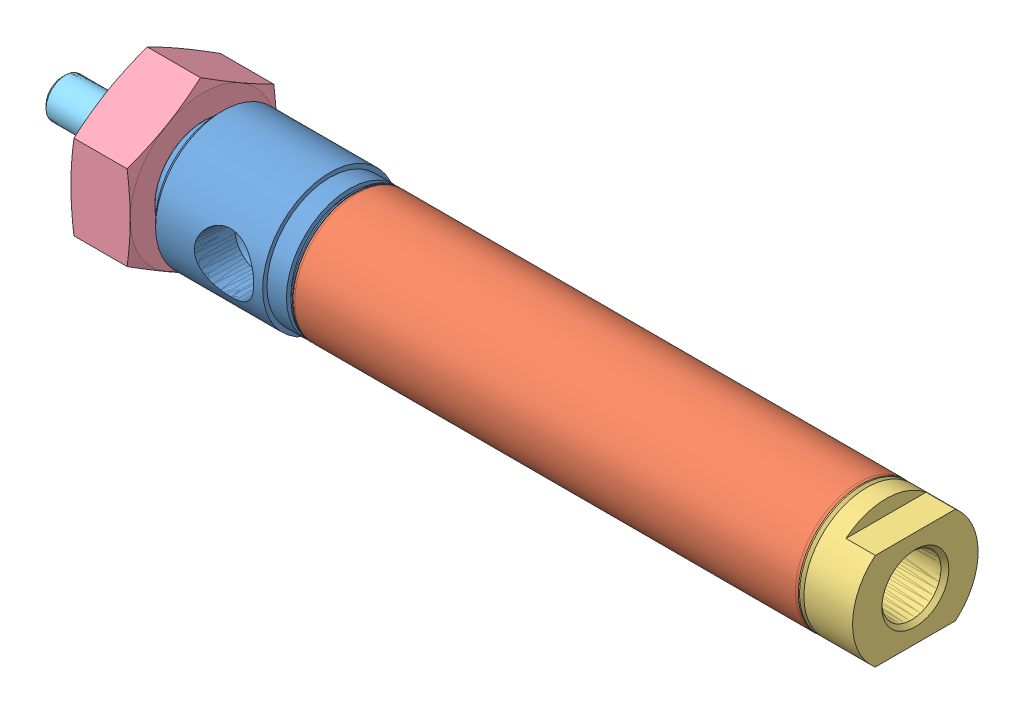
SolidWorks assembly 042-D, configuration Default. Lengths in mm.
Overall size (138.94 27.57 23.88).
6 component instances, 6 part files, 14 mates.
Components (placement in the parent):
- 042-DC0000_0_dummy-1: 042-DC0000_0_dummy [Default] at origin
- 04R000-0_rod_guide-1: 04R000-0_rod_guide [Default] at origin size (40.49 21.91 21.91)
- 04R-3_25650C-1: 04R-3_25650C [Default] at (34.8361 0 0) size (84.07 20.51 20.51)
- 040000_rear_head-1: 040000_rear_head [Default] at (112.7506 0 0) size (13.49 20.45 20.45)
- D-9-1: D-9 [Default] at (10.3124 0 0) x (0 0 -1) z (1 0 0) size (23.88 27.57 9.65)
- C-042-D0_rod-1: C-042-D0_rod [Default] at origin size (125.45 19.24 19.24)
Mates (geometry in assembly coordinates):
- Distance2: distance = 0 mm aligned: plane of 04R000-0_rod_guide-1 through (0 0 0) normal (1 0 0); plane of 042-DC0000_0_dummy-1 through (0 0 0) normal (1 0 0)
- Coincident1: coincident aligned: line of 042-DC0000_0_dummy-1 through (80.9 0 0) axis (-1 0 0); line of 04R000-0_rod_guide-1 through (80.9 0 0) axis (-1 0 0)
- Angle3: planar angle = 0 rad aligned: plane of 04R000-0_rod_guide-1 through (0 0 0) normal (0 0 -1); plane of 042-DC0000_0_dummy-1 through (0 0 0) normal (0 0 -1)
- Distance4: distance = 0 mm aligned: plane of 04R-3_25650C-1 through (34.8361 0 0) normal (1 0 0); plane of 04R000-0_rod_guide-1 through (34.8361 0 0) normal (1 0 0)
- Coincident2: coincident aligned: line of 04R000-0_rod_guide-1 through (80.9 0 0) axis (-1 0 0); line of 04R-3_25650C-1 through (115.7361 0 0) axis (-1 0 0)
- Angle6: planar angle = 0 rad aligned: plane of 04R-3_25650C-1 through (34.8361 0 0) normal (0 0 -1); plane of 04R000-0_rod_guide-1 through (0 0 0) normal (0 0 -1)
- Distance6: distance = 0 mm aligned: plane of 040000_rear_head-1 through (117.5512 0 0) normal (1 0 0); plane of 04R-3_25650C-1 through (117.5512 0 0) normal (1 0 0)
- Coincident3: coincident aligned: line of 04R-3_25650C-1 through (115.7361 0 0) axis (-1 0 0); line of 040000_rear_head-1 through (193.6506 0 0) axis (-1 0 0)
- Angle9: planar angle = 0 rad aligned: plane of 040000_rear_head-1 through (112.7506 0 0) normal (0 0 -1); plane of 04R-3_25650C-1 through (34.8361 0 0) normal (0 0 -1)
- Distance8: distance = 0 mm aligned: plane of D-9-1 through (10.3124 0 0) normal (1 0 0); plane of 04R000-0_rod_guide-1 through (10.3124 0 0) normal (1 0 0)
- Coincident4: coincident aligned: line of 04R000-0_rod_guide-1 through (80.9 0 0) axis (-1 0 0); line of D-9-1 through (91.2124 0 0) axis (-1 0 0)
- Angle12: planar angle = 0 rad aligned: plane of D-9-1 through (10.3124 0 0) normal (0 0 -1); plane of 04R000-0_rod_guide-1 through (0 0 0) normal (0 0 -1)
- LimitDistance2: limit distance = 0 mm aligned: plane of C-042-D0_rod-1 through (0 0 0) normal (1 0 0); plane of 04R000-0_rod_guide-1 through (0 0 0) normal (1 0 0)
- Coincident5: coincident aligned: line of 04R000-0_rod_guide-1 through (80.9 0 0) axis (-1 0 0); line of C-042-D0_rod-1 through (80.9 0 0) axis (-1 0 0)
